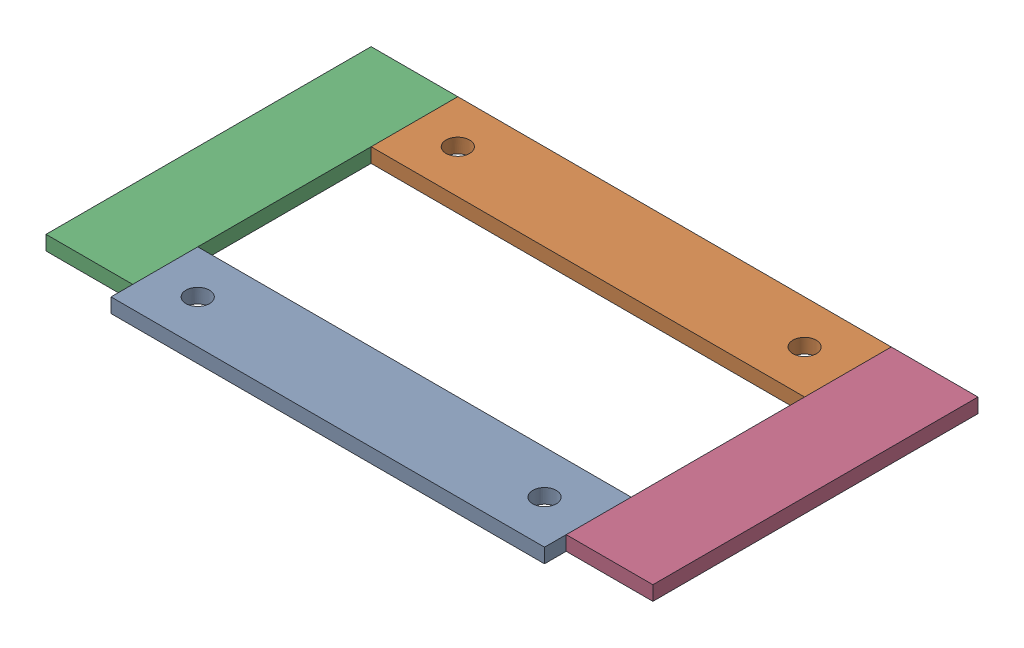
SolidWorks assembly 01-059-00-0, configuration Default. Lengths in mm.
Overall size (533.4 12.7 304.8).
4 component instances, 2 part files, 12 mates.
Components (placement in the parent):
- 01-057-00-0-1: 01-057-00-0 [Default] at origin size (381 12.7 76.2)
- 01-057-00-0-2: 01-057-00-0 [Default] at (0 0 -228.6) size (381 12.7 76.2)
- 01-058-00-0-1: 01-058-00-0 [Default] at (-76.2 0 -304.8) x (0 0 1) z (-1 0 0) size (285.75 12.7 76.2)
- 01-058-00-0-2: 01-058-00-0 [Default] at (381 0 -304.8) x (0 0 1) z (-1 0 0) size (285.75 12.7 76.2)
Mates (geometry in assembly coordinates):
- Distance1: distance = 152.4 mm anti-aligned: plane of 01-057-00-0-2 through (0 12.7 -228.6) normal (0 0 1); plane of 01-057-00-0-1 through (0 12.7 -76.2) normal (0 0 -1)
- Coincident2: coincident anti-aligned: plane of 01-057-00-0-2 through (0 0 -304.8) normal (0 -1 0); plane of assembly through (0 0 0) normal (0 1 0)
- Coincident3: coincident anti-aligned: plane of 01-057-00-0-1 through (0 0 -76.2) normal (0 -1 0); plane of assembly
- Coincident4: coincident aligned: plane of 01-057-00-0-1 through (0 12.7 0) normal (0 0 1); plane of assembly
- Coincident5: coincident anti-aligned: plane of 01-057-00-0-1 through (0 12.7 0) normal (-1 0 0); plane of assembly
- Coincident6: coincident anti-aligned: plane of 01-057-00-0-2 through (0 12.7 -228.6) normal (-1 0 0); plane of assembly
- Coincident7: coincident aligned: plane of 01-057-00-0-2 through (0 12.7 -304.8) normal (0 0 -1); plane of 01-058-00-0-1 through (-76.2 12.7 -304.8) normal (0 0 -1)
- Coincident8: coincident anti-aligned: plane of 01-057-00-0-2 through (0 12.7 -228.6) normal (-1 0 0); plane of 01-058-00-0-1 through (0 12.7 -304.8) normal (1 0 0)
- Coincident9: coincident anti-aligned: plane of 01-058-00-0-1 through (0 0 -304.8) normal (0 -1 0); plane of assembly
- Coincident10: coincident aligned: plane of 01-057-00-0-2 through (0 12.7 -304.8) normal (0 0 -1); plane of 01-058-00-0-2 through (381 12.7 -304.8) normal (0 0 -1)
- Coincident11: coincident anti-aligned: plane of 01-058-00-0-2 through (457.2 0 -304.8) normal (0 -1 0); plane of assembly
- Coincident12: coincident anti-aligned: plane of 01-057-00-0-2 through (381 12.7 -228.6) normal (1 0 0); plane of 01-058-00-0-2 through (381 12.7 -304.8) normal (-1 0 0)
